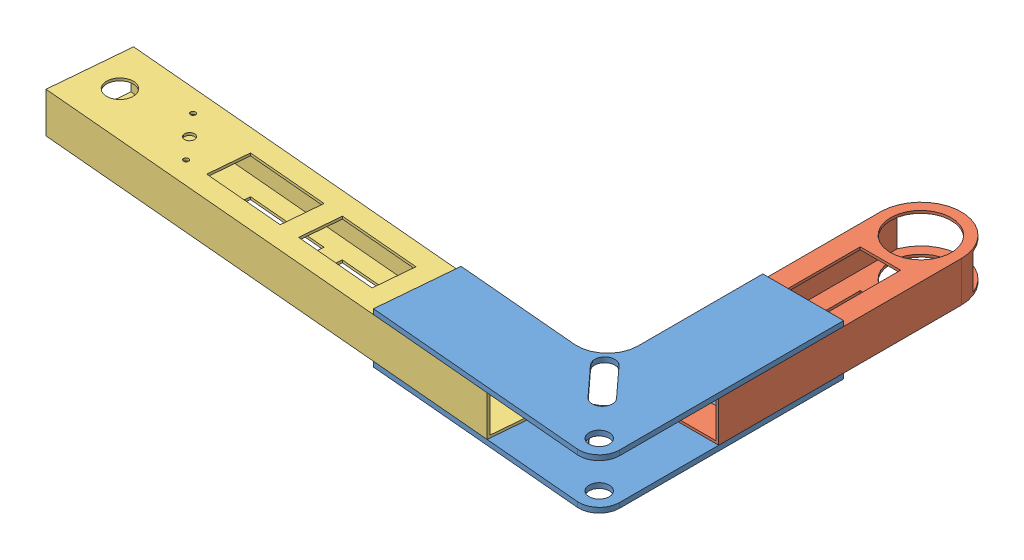
SolidWorks assembly Assem1, configuration Default. Lengths in mm.
Overall size (391.86 31.75 253.93).
4 component instances, 3 part files, 7 mates.
Components (placement in the parent):
- FrontClawBrace-1: FrontClawBrace [Default] at (232.6319 169.547 377.0862) x (-0.996195 0 -0.087156) z (0 1 0) size (153.56 154.13 3.17)
- FrontClawBrace-2: FrontClawBrace [Default] at (232.6319 198.122 377.0862) x (-0.996195 0 -0.087156) z (0 1 0) size (153.56 154.13 3.17)
- FrontDriveWheelMount-1: FrontDriveWheelMount [Default] at (359.1487 185.422 161.8463) size (50.8 25.4 177.8)
- FrontClawMotorMount-1: FrontClawMotorMount [Default] at (310.8246 185.422 383.9272) x (-0.087156 0 0.996195) z (-0.996195 0 -0.087156) size (50.8 25.4 304.8)
Mates (geometry in assembly coordinates):
- Coincident5: coincident: plane of FrontClawBrace-1 through (230.4182 172.722 402.3896) normal (-0.996195 0 -0.087156); plane of FrontClawBrace-2 through (230.4182 201.297 402.3896) normal (-0.996195 0 -0.087156)
- Coincident13: coincident: plane of FrontClawBrace-2 through (384.5487 201.297 261.155) normal (1 0 0); plane of FrontDriveWheelMount-1 through (384.5487 172.722 339.6463) normal (1 0 0)
- Coincident14: coincident: plane of FrontClawBrace-1 through (314.6987 172.722 339.6463) normal (0 1 0); plane of FrontDriveWheelMount-1 through (384.5487 172.722 339.6463) normal (0 -1 0)
- Coincident15: coincident: point of FrontClawBrace-1; point of FrontDriveWheelMount-1
- Coincident16: coincident: plane of FrontClawBrace-1 through (234.8457 172.722 351.7829) normal (0.087156 0 -0.996195); plane of FrontClawMotorMount-1 through (9.3982 172.722 332.0588) normal (0.087156 0 -0.996195)
- Coincident17: coincident: plane of FrontClawBrace-2 through (314.6987 198.122 339.6463) normal (0 -1 0); plane of FrontClawMotorMount-1 through (4.9707 198.122 382.6655) normal (0 1 0)
- Coincident18: coincident: point of FrontClawBrace-1; point of FrontClawMotorMount-1
